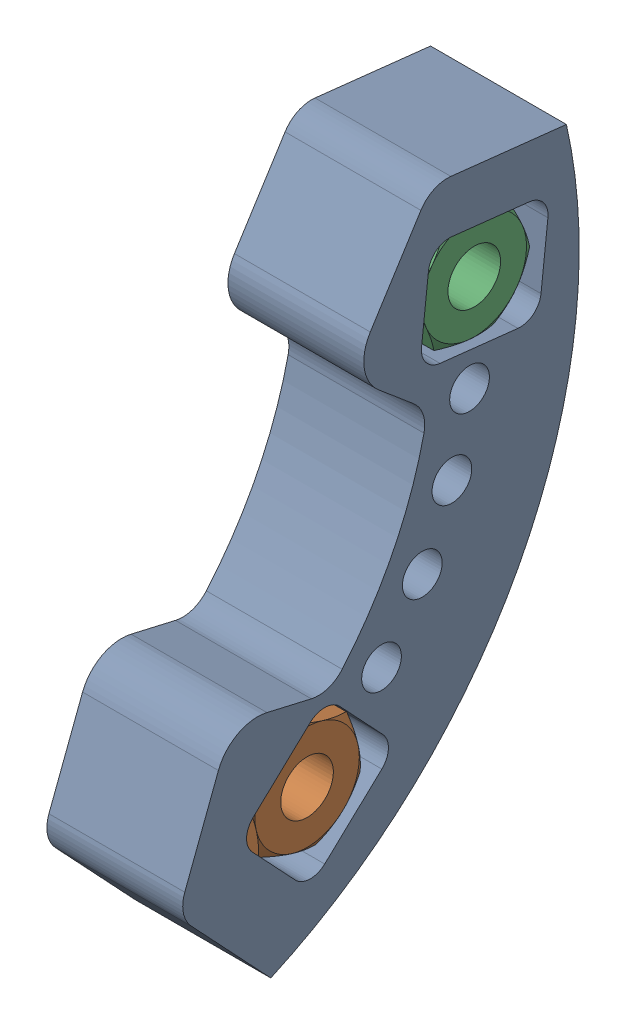
SolidWorks assembly MFG CW Right Brake Limiter Asmbly, configuration Default. Lengths in mm.
Overall size (13 57.83 37.94).
3 component instances, 2 part files, 0 mates.
Components (placement in the parent):
- MFG CW Right Brake Limiter-1: MFG CW Right Brake Limiter [Default] at origin size (13 57.83 37.94)
- M6 x 1 Hex Nut-1: M6 x 1 Hex Nut [Default] at (127.5 76.4725 72.1408) x (0 -0.224951 0.97437) z (-1 0 0) size (10 11.55 5)
- M6 x 1 Hex Nut-2: M6 x 1 Hex Nut [Default] at (127.5 110.7884 56.139) x (0 0.993961 -0.109734) z (1 0 0) size (10 11.55 5)
